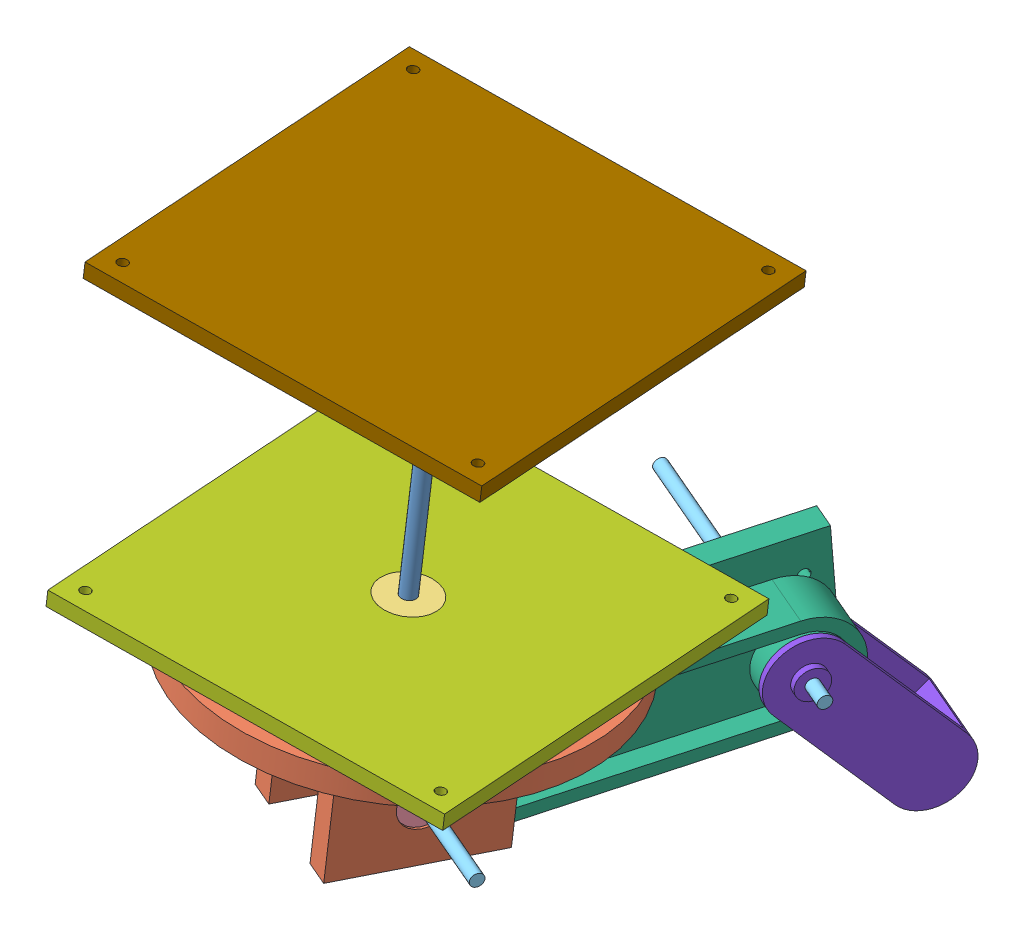
SolidWorks assembly Assem1, configuration Default. Lengths in mm.
Overall size (199.18 253.44 280.22).
14 component instances, 9 part files, 23 mates.
Components (placement in the parent):
- Shaft 6mm-1: Shaft 6mm [Default] at (-44.4566 155.7335 141.9378) x (0.709865 -0.090568 -0.69849) z (-0.699403 0.026539 -0.714234) size (6 130 6)
- Base1-1: Base1 [Default] at (-55.2757 26.3138 147.7233) x (-0.359708 0.071659 0.930309) z (0.083224 0.995537 -0.044504) size (150 150 70)
- Ball Bearing 6mm-4: Ball Bearing 6mm [Default] at (-53.528 47.22 146.7888) x (0.985736 -0.075685 0.150318) z (0.146279 -0.056379 -0.987635) size (22 6 22)
- Ball Bearing 5mm-2: Ball Bearing 5mm [Default] at (-76.0625 -9.9515 142.4794) x (-0.207397 0.728955 0.652388) z (-0.305455 -0.681801 0.664714) size (18 5 18)
- Ball Bearing 5mm-4: Ball Bearing 5mm [Default] at (-36.1006 -12.5924 158.1343) x (-0.324053 0.336868 0.884031) z (-0.176935 -0.939547 0.293165) size (18 5 18)
- Shaft 5mm-2: Shaft 5mm [Default] at (0.4887 -15.0104 172.468) x (-0.207397 0.728955 0.652388) z (-0.305455 -0.681801 0.664714) size (5 120 5)
- Link1-2: Link1 [Default] at (-23.3634 -16.916 93.3032) x (0.368399 0.088935 -0.925404) z (0.024456 0.994142 0.105277) size (169.77 45 40.23)
- Bed1-5: Bed1 [Default] at (-53.528 47.22 146.7888) x (0.991225 -0.087301 -0.099254) z (-0.083224 -0.995537 0.044504) size (150 150 6)
- Link2-2: Link2 [Default] at (-20.8426 -31.9989 6.0417) x (0.199405 -0.746392 -0.63493) z (-0.310731 -0.662666 0.68141) size (90 32.5 30)
- Shaft 5mm-3: Shaft 5mm [Default] at (-99.9696 -4.7734 -3.5645) x (0.346995 0.482174 -0.804427) z (0.126139 -0.87392 -0.469417) size (5 120 5)
- Ball Bearing 5mm-6: Ball Bearing 5mm [Default] at (-26.3601 -9.6379 25.2716) x (-0.178865 -0.937521 0.298432) z (-0.322992 0.342465 0.882266) size (18 5 18)
- Ball Bearing 5mm-7: Ball Bearing 5mm [Default] at (-2.1971 -11.2347 34.7374) x (0.160243 0.955448 -0.247872) z (-0.332623 0.288698 0.897783) size (18 5 18)
- Bed-1: Bed [Default] at (-43.5411 166.6844 141.4483) x (0.102697 0.035853 0.994066) z (-0.083224 -0.995537 0.044504) size (150 150 6)
- Ball Bearing 5mm-8: Ball Bearing 5mm [Default] at (-37.5123 -8.9009 20.9028) x (0.186291 0.929346 -0.318766) z (-0.318766 0.364066 0.875125) size (18 5 18)
Mates (geometry in assembly coordinates):
- Concentric20: concentric aligned: cylinder of Shaft 6mm-1 through (-55.2757 26.3138 147.7233) axis (0.083224 0.995537 -0.044504) radius 3; cylinder of Ball Bearing 6mm-4 through (-54.0273 41.2468 147.0558) axis (0.083224 0.995537 -0.044504) radius 3
- Concentric23: concentric aligned: line of Shaft 6mm-1 through (-55.2757 26.3138 147.7233) axis (0.083224 0.995537 -0.044504); cylinder of Base1-1 through (-55.2758 26.3128 147.7234) axis (0.083224 0.995537 -0.044504) radius 3
- Coincident23: coincident aligned: plane of Shaft 6mm-1 through (-55.2757 26.3138 147.7233) normal (-0.083224 -0.995537 0.044504); plane of Base1-1 through (-55.2757 26.3138 147.7233) normal (-0.083224 -0.995537 0.044504)
- Concentric25: concentric anti-aligned: cylinder of Base1-1 through (11.296 -15.7246 176.7017) axis (-0.929346 0.061416 -0.364066) radius 9; cylinder of Ball Bearing 5mm-2 through (-80.7092 -9.6444 140.6591) axis (0.929346 -0.061416 0.364066) radius 9
- Concentric26: concentric anti-aligned: cylinder of Base1-1 through (11.296 -15.7246 176.7017) axis (-0.929346 0.061416 -0.364066) radius 9; cylinder of Ball Bearing 5mm-4 through (-40.7474 -12.2853 156.314) axis (0.929346 -0.061416 0.364066) radius 9
- Concentric28: concentric aligned: cylinder of Ball Bearing 5mm-2 through (-80.7092 -9.6444 140.6591) axis (0.929346 -0.061416 0.364066) radius 2.5; cylinder of Shaft 5mm-2 through (-111.0328 -7.6405 128.78) axis (0.929346 -0.061416 0.364066) radius 2.5
- Coincident29: coincident aligned: circle of Ball Bearing 6mm-4; circle of Bed1-5
- Coincident32: coincident aligned: plane of Ball Bearing 6mm-4 through (-54.0273 41.2468 147.0558) normal (-0.083224 -0.995537 0.044504); plane of Bed1-5 through (-54.0273 41.2468 147.0558) normal (-0.083224 -0.995537 0.044504)
- Concentric33: concentric anti-aligned: line of Link1-2 through (-9.6319 -10.7433 31.8248) axis (0.929346 -0.061416 0.364066); cylinder of Shaft 5mm-3 through (11.5519 -12.1433 40.1235) axis (-0.929346 0.061416 -0.364066) radius 2.5
- Distance3: distance = 5 mm anti-aligned: plane of Base1-1 through (-54.4435 36.2691 147.2783) normal (0.083224 0.995537 -0.044504); plane of Bed1-5 through (-54.0273 41.2468 147.0558) normal (-0.083224 -0.995537 0.044504)
- Distance9: distance = 1 mm anti-aligned: plane of Link2-2 through (0.4021 9.8398 34.4042) normal (-0.929346 0.061416 -0.364066); plane of Link1-2 through (-25.2221 -16.7931 92.5751) normal (0.929346 -0.061416 0.364066)
- Concentric41: concentric anti-aligned: cylinder of Link1-2 through (-23.5721 -9.8221 26.3638) axis (0.929346 -0.061416 0.364066) radius 9; cylinder of Ball Bearing 5mm-6 through (-21.7134 -9.9449 27.092) axis (-0.929346 0.061416 -0.364066) radius 9
- Concentric42: concentric aligned: cylinder of Link1-2 through (-23.5721 -9.8221 26.3638) axis (0.929346 -0.061416 0.364066) radius 9; cylinder of Ball Bearing 5mm-7 through (-6.8439 -10.9276 32.917) axis (0.929346 -0.061416 0.364066) radius 9
- Coincident49: coincident aligned: plane of Link1-2 through (-25.2221 -16.7931 92.5751) normal (0.929346 -0.061416 0.364066); plane of Ball Bearing 5mm-7 through (-2.1971 -11.2347 34.7374) normal (0.929346 -0.061416 0.364066)
- Concentric44: concentric aligned: cylinder of Link2-2 through (1.0556 -11.4496 36.0116) axis (-0.929346 0.061416 -0.364066) radius 2.5; cylinder of Shaft 5mm-3 through (11.5519 -12.1433 40.1235) axis (-0.929346 0.061416 -0.364066) radius 2.5
- Distance10: distance = 4.5 mm anti-aligned: plane of Link1-2 through (-25.2221 -16.7931 92.5751) normal (0.929346 -0.061416 0.364066); plane of Base1-1 through (-57.1202 -32.1899 183.7639) normal (-0.929346 0.061416 -0.364066)
- Coincident51: coincident anti-aligned: plane of Base1-1 through (-40.7474 -12.2853 156.314) normal (0.929346 -0.061416 0.364066); plane of Ball Bearing 5mm-4 through (-40.7474 -12.2853 156.314) normal (-0.929346 0.061416 -0.364066)
- Coincident52: coincident anti-aligned: plane of Base1-1 through (-76.0625 -9.9515 142.4794) normal (-0.929346 0.061416 -0.364066); plane of Ball Bearing 5mm-2 through (-76.0625 -9.9515 142.4794) normal (0.929346 -0.061416 0.364066)
- Distance11: distance = 120 mm aligned: plane of Bed-1 through (-43.5411 166.6844 141.4483) normal (0.083224 0.995537 -0.044504); plane of Bed1-5 through (-53.528 47.22 146.7888) normal (0.083224 0.995537 -0.044504)
- Parallel3: parallel: plane of Bed1-5 through (-128.3692 47.7944 154.4999) normal (-0.991225 0.087301 0.099254); line of Bed-1 through (-126.0846 164.5698 74.6044) axis (0.102697 0.035853 0.994066)
- Coincident58: coincident aligned: cylinder of Bed1-5 through (-112.8821 59.4751 220.0547) axis (-0.083224 -0.995537 0.044504) radius 2; circle of Bed-1
- Concentric45: concentric aligned: cylinder of Link1-2 through (-44.0177 -8.471 18.3544) axis (0.929346 -0.061416 0.364066) radius 9; cylinder of Ball Bearing 5mm-8 through (-42.159 -8.5938 19.0825) axis (0.929346 -0.061416 0.364066) radius 9
- Coincident61: coincident anti-aligned: plane of Link1-2 through (-37.5123 -8.9009 20.9028) normal (-0.929346 0.061416 -0.364066); plane of Ball Bearing 5mm-8 through (-37.5123 -8.9009 20.9028) normal (0.929346 -0.061416 0.364066)
